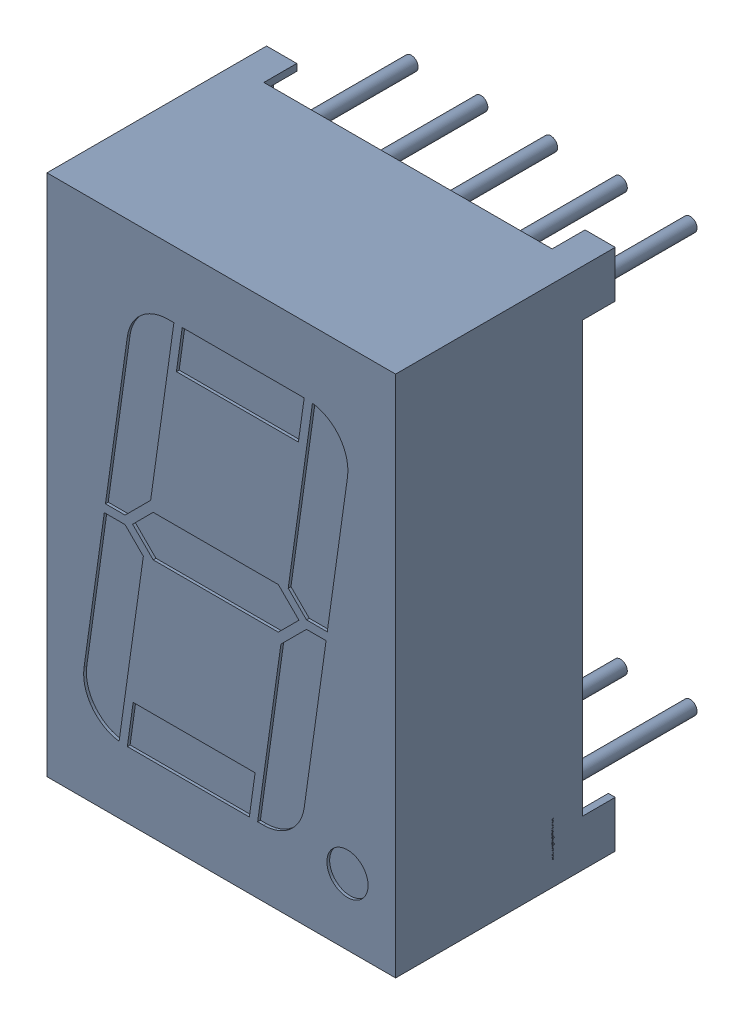
SolidWorks assembly Disp_SA56-11, configuration Default. Lengths in mm.
Overall size (12.7 19.05 12).
3 component instances, 1 part files, 0 mates.
Components (placement in the parent):
- SW3dPS-Disp_SA56-11_2-1: SW3dPS-Disp_SA56-11_2 [Default] at origin size (12.7 19.05 12)
  - SW3dPS-Disp_SA56-11_Open_CASCADE_STEP_translator_6.2_78.2_2-1: SW3dPS-Disp_SA56-11_Open_CASCADE_STEP_translator_6.2_78.2_2 [Default] at origin size (12.7 19.05 12)
    - SW3dPS-Disp_SA56-11_Disp_SA56-12-1: SW3dPS-Disp_SA56-11_Disp_SA56-12 [Default] at (5.0801 7.6201 8.0327) x (1 0 0) z (0 -1 0) size (12.7 12 19.05)
